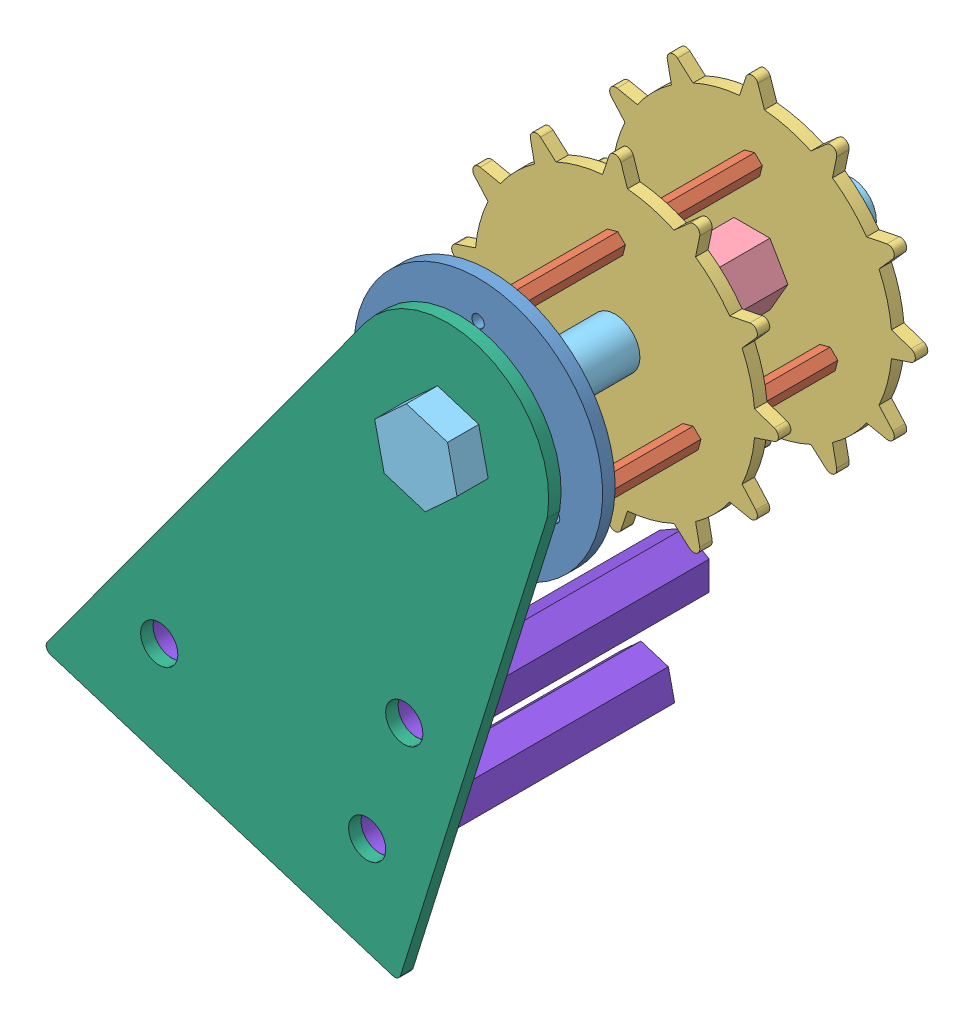
SolidWorks assembly 传动轮, configuration 默认. Lengths in mm.
Overall size (90.9 107.76 70).
17 component instances, 8 part files, 31 mates.
Components (placement in the parent):
- 外侧圆板-1: 外侧圆板 [默认] at (-112.3007 -16.3228 -1) size (40 40 2)
- 齿铜柱-1: 齿铜柱 [默认] at (-124.425 -23.3228 -21) size (3.34 3.35 20)
- 齿铜柱-2: 齿铜柱 [默认] at (-100.1763 -23.3228 -21) x (-0.5 0.866025 0) z (0 0 1) size (3.34 3.35 20)
- 齿铜柱-3: 齿铜柱 [默认] at (-112.3007 -2.3228 -21) x (-0.5 -0.866025 0) z (0 0 1) size (3.34 3.35 20)
- 齿-1: 齿 [默认] at (-112.3007 -16.3228 -23) size (52.5 52.5 2)
- 齿内测铜柱-1: 齿内测铜柱 [默认] at (-112.3007 -16.3228 -43) size (11.55 10 20)
- 齿铜柱-4: 齿铜柱 [默认] at (-100.1763 -23.3228 -43) x (-0.5 0.866025 0) z (0 0 1) size (3.34 3.35 20)
- 齿铜柱-5: 齿铜柱 [默认] at (-112.3007 -2.3228 -43) x (-0.5 -0.866025 0) z (0 0 1) size (3.34 3.35 20)
- 齿铜柱-6: 齿铜柱 [默认] at (-124.425 -23.3228 -43) size (3.34 3.35 20)
- 齿-2: 齿 [默认] at (-112.3007 -16.3228 -45) size (52.5 52.5 2)
- 传动轮螺栓-1: 传动轮螺栓 [默认] at (-112.3007 -16.3228 -59) x (-0.980386 -0.197089 0) z (0 0 1) size (12.15 13.85 70)
- 最外侧支撑板-1: 最外侧支撑板 [默认] at (-120.0559 -95.5444 4) x (0.954528 -0.29812 0) z (0 0 1) size (59.6 94.28 2)
- 8M螺母-1: 8M螺母 [默认] at (-112.3007 -16.3228 1) x (0.96573 0.25955 0) z (0 0 1) size (10.23 11.54 3)
- 8M螺母-2: 8M螺母 [默认] at (-112.3007 -16.3228 -48) size (10.23 11.54 3)
- 43铜柱-1: 43铜柱 [默认] at (-119.167 -59.1547 -39) x (0.999179 -0.040516 0) z (0 0 1) size (8.18 9.23 43)
- 43铜柱-2: 43铜柱 [默认] at (-158.5379 -67.8111 -39) x (-0.336549 -0.941666 0) z (0 0 1) size (8.18 9.23 43)
- 43铜柱-3: 43铜柱 [默认] at (-125.1294 -78.2453 -39) x (-0.336549 -0.941666 0) z (0 0 1) size (8.18 9.23 43)
Mates (geometry in assembly coordinates):
- 同心1: concentric: cylinder of assembly; cylinder of assembly; cylinder of 外侧圆板-1 through (-124.425 -23.3228 -1) axis (0 0 1) radius 1; cylinder of 齿铜柱-1 through (-124.425 -23.3228 -21) axis (0 0 1) radius 1
- 重合1: coincident: plane of assembly; plane of assembly; plane of 外侧圆板-1 through (-112.3007 -16.3228 -1) normal (0 0 -1); plane of 齿铜柱-1 through (-124.425 -23.3228 -1) normal (0 0 1)
- 同心2: concentric: cylinder of assembly; cylinder of assembly; cylinder of 齿铜柱-3 through (-112.3007 -2.3228 -21) axis (0 0 1) radius 1; cylinder of 齿-1 through (-112.3007 -2.3228 -23) axis (0 0 1) radius 1
- 重合2: coincident: plane of assembly; plane of assembly; plane of 齿铜柱-3 through (-112.3007 -2.3228 -21) normal (0 0 -1); plane of 齿-1 through (-112.3007 -16.3228 -21) normal (0 0 1)
- 同心3: concentric: cylinder of assembly; cylinder of assembly; cylinder of 齿铜柱-2 through (-100.1763 -23.3228 -21) axis (0 0 1) radius 1; cylinder of 齿-1 through (-100.1763 -23.3228 -23) axis (0 0 1) radius 1
- 同心4: concentric: cylinder of assembly; cylinder of assembly; cylinder of 外侧圆板-1 through (-100.1763 -23.3228 -1) axis (0 0 1) radius 1; cylinder of 齿铜柱-2 through (-100.1763 -23.3228 -21) axis (0 0 1) radius 1
- 同心5: concentric: cylinder of assembly; cylinder of assembly; cylinder of 齿-1 through (-112.3007 -16.3228 -23) axis (0 0 1) radius 4; cylinder of 齿内测铜柱-1 through (-112.3007 -16.3228 -43) axis (0 0 1) radius 4
- 重合3: coincident: plane of assembly; plane of assembly; plane of 齿-1 through (-112.3007 -16.3228 -23) normal (0 0 -1); plane of 齿内测铜柱-1 through (-112.3007 -16.3228 -23) normal (0 0 1)
- 同心6: concentric: cylinder of assembly; cylinder of assembly; cylinder of 齿-1 through (-100.1763 -23.3228 -23) axis (0 0 1) radius 1; cylinder of 齿铜柱-4 through (-100.1763 -23.3228 -43) axis (0 0 1) radius 1
- 重合4: coincident: plane of assembly; plane of assembly; plane of 齿-1 through (-112.3007 -16.3228 -23) normal (0 0 -1); plane of 齿铜柱-4 through (-100.1763 -23.3228 -23) normal (0 0 1)
- 同心7: concentric: cylinder of assembly; cylinder of assembly; cylinder of 齿铜柱-4 through (-100.1763 -23.3228 -43) axis (0 0 1) radius 1; cylinder of 齿-2 through (-100.1763 -23.3228 -45) axis (0 0 1) radius 1
- 同心8: concentric: cylinder of assembly; cylinder of assembly; cylinder of 齿铜柱-5 through (-112.3007 -2.3228 -43) axis (0 0 1) radius 1; cylinder of 齿-2 through (-112.3007 -2.3228 -45) axis (0 0 1) radius 1
- 重合5: coincident: plane of assembly; plane of assembly; plane of 齿铜柱-5 through (-112.3007 -2.3228 -43) normal (0 0 -1); plane of 齿-2 through (-112.3007 -16.3228 -43) normal (0 0 1)
- 同心9: concentric: cylinder of assembly; cylinder of assembly; cylinder of 齿内测铜柱-1 through (-112.3007 -16.3228 -43) axis (0 0 1) radius 4; cylinder of 传动轮螺栓-1 through (-112.3007 -16.3228 6) axis (0 0 -1) radius 4
- 重合6: coincident: plane of assembly; plane of assembly; plane of 传动轮螺栓-1 through (-112.3007 -16.3228 6) normal (0 0 -1); plane of 最外侧支撑板-1 through (-120.0559 -95.5444 6) normal (0 0 1)
- 同心12: concentric: cylinder of 传动轮螺栓-1 through (-112.3007 -16.3228 6) axis (0 0 -1) radius 4; cylinder of ? through (-112.3007 -16.3228 1) axis (0 0 1) radius 4
- 重合7: coincident: plane of 最外侧支撑板-1 through (-120.0559 -95.5444 4) normal (0 0 -1); plane of ? through (-112.3007 -16.3228 4) normal (0 0 1)
- 重合8: coincident: plane of 外侧圆板-1 through (-112.3007 -16.3228 1) normal (0 0 1); plane of ? through (-112.3007 -16.3228 1) normal (0 0 -1)
- 同心14: concentric: cylinder of assembly; cylinder of assembly; cylinder of 传动轮螺栓-1 through (-112.3007 -16.3228 6) axis (0 0 -1) radius 4; cylinder of 8M螺母-2 through (-112.3007 -16.3228 -48) axis (0 0 1) radius 4
- 重合9: coincident: plane of assembly; plane of assembly; plane of 齿-2 through (-112.3007 -16.3228 -45) normal (0 0 -1); plane of 8M螺母-2 through (-112.3007 -16.3228 -45) normal (0 0 1)
- 同心15: concentric: cylinder of assembly; cylinder of assembly; cylinder of 最外侧支撑板-1 through (-119.167 -59.1547 4) axis (0 0 1) radius 3; cylinder of 43铜柱-1 through (-119.167 -59.1547 -39.001) axis (0 0 1) radius 3
- 重合10: coincident: plane of assembly; plane of assembly; plane of 最外侧支撑板-1 through (-120.0559 -95.5444 4) normal (0 0 -1); plane of 43铜柱-1 through (-119.167 -59.1547 4) normal (0 0 1)
- 同心16: concentric: cylinder of assembly; cylinder of assembly; cylinder of 最外侧支撑板-1 through (-125.1294 -78.2453 4) axis (0 0 1) radius 3; cylinder of 43铜柱-3 through (-125.1294 -78.2453 -39.001) axis (0 0 1) radius 3
- 重合11: coincident: plane of assembly; plane of assembly; plane of 最外侧支撑板-1 through (-120.0559 -95.5444 4) normal (0 0 -1); plane of 43铜柱-3 through (-125.1294 -78.2453 4) normal (0 0 1)
- 同心17: concentric: cylinder of assembly; cylinder of assembly; cylinder of 最外侧支撑板-1 through (-158.5379 -67.8111 4) axis (0 0 1) radius 3; cylinder of 43铜柱-2 through (-158.5379 -67.8111 -39.001) axis (0 0 1) radius 3
- 重合12: coincident: plane of assembly; plane of assembly; plane of 最外侧支撑板-1 through (-120.0559 -95.5444 4) normal (0 0 -1); plane of 43铜柱-2 through (-158.5379 -67.8111 4) normal (0 0 1)
- 平行1: parallel: plane of assembly; plane of assembly; plane of 传动轮螺栓-1 through (-117.396 -21.0172 11) normal (-0.29812 -0.954528 0); plane of 最外侧支撑板-1 through (-120.0559 -95.5444 6) normal (-0.29812 -0.954528 0)
- 平行2: parallel: plane of assembly; plane of 43铜柱-1 through (-115.167 -61.4641 4) normal (1 0 0); plane of assembly
- 平行3: parallel: plane of assembly; plane of assembly; plane of 43铜柱-2 through (-161.9348 -70.9407 4) normal (-0.29812 -0.954528 0); plane of 最外侧支撑板-1 through (-120.0559 -95.5444 6) normal (-0.29812 -0.954528 0)
- 平行4: parallel: plane of assembly; plane of assembly; plane of 43铜柱-3 through (-128.5263 -81.3749 4) normal (-0.29812 -0.954528 0); plane of 最外侧支撑板-1 through (-120.0559 -95.5444 6) normal (-0.29812 -0.954528 0)
- 平行7: parallel: plane of assembly; plane of assembly; plane of 最外侧支撑板-1 through (-120.0559 -95.5444 6) normal (-0.29812 -0.954528 0); plane of 8M螺母-1 through (-116.5468 -20.2348 4) normal (-0.29812 -0.954528 0)
